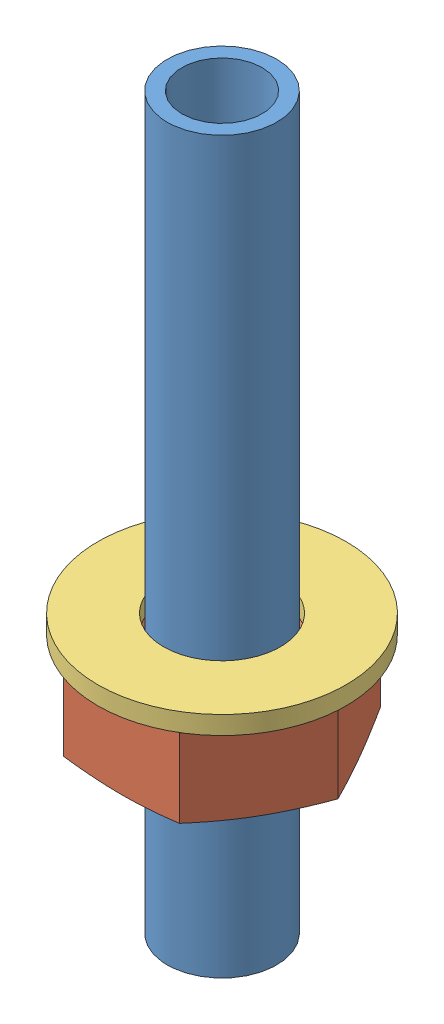
SolidWorks assembly BellcrankTube, configuration Default. Lengths in mm.
Overall size (6.8 20 6.8).
3 component instances, 3 part files, 4 mates.
Components (placement in the parent):
- BrassTube1-1: BrassTube1 [Default] at origin size (3 20 3)
- Nut-1: Nut [Default] at (0 4.6 0) size (6.35 2.5 5.5)
- M3-washer-1: M3-washer [Default] at (0 7.1 0) size (6.8 0.5 6.8)
Mates (geometry in assembly coordinates):
- Concentric1: concentric aligned: cylinder of BrassTube1-1; cylinder of Nut-1
- Concentric2: concentric aligned: cylinder of BrassTube1-1; cylinder of M3-washer-1
- Coincident1: coincident anti-aligned: plane of Nut-1 through (-4.7631 7.1 -2.75) normal (0 1 0); plane of M3-washer-1 through (0 7.1 0) normal (0 -1 0)
- Distance1: distance = 12.4 mm aligned: plane of BrassTube1-1 through (0 20 0) normal (0 1 0); plane of M3-washer-1 through (0 7.6 0) normal (0 1 0)
